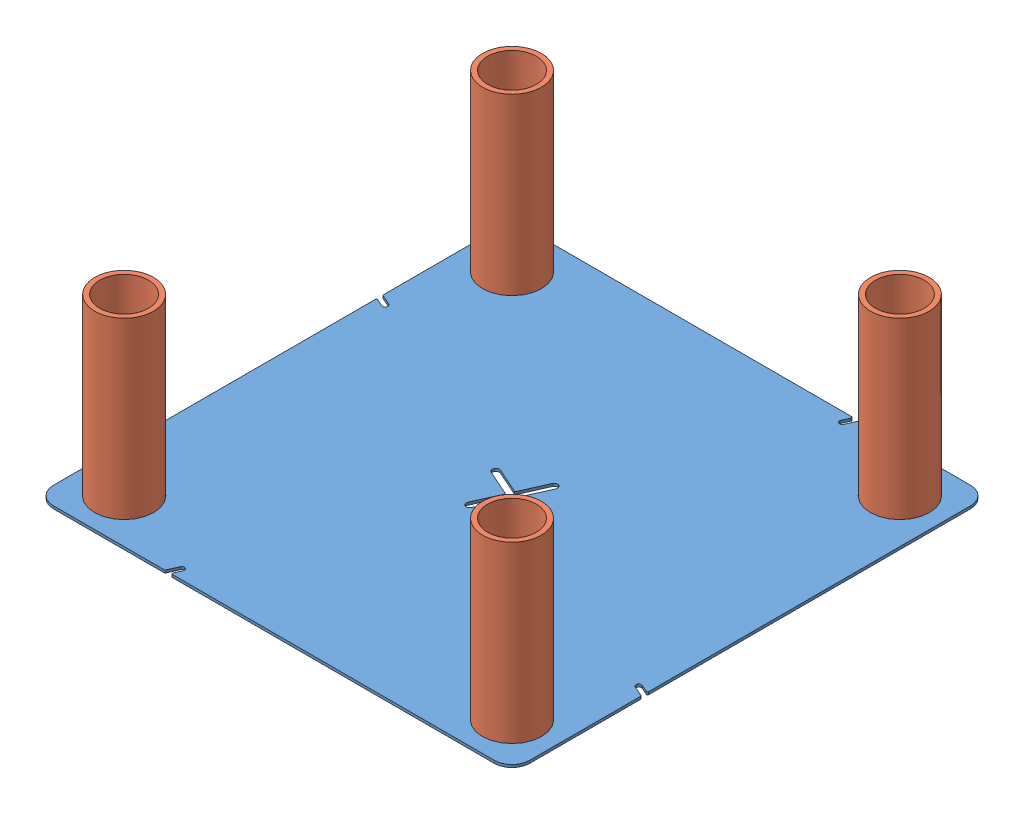
SolidWorks assembly GE-22304, configuration Default. Lengths in mm.
Overall size (341.88 127 341.88).
5 component instances, 2 part files, 11 mates.
Components (placement in the parent):
- GE-22304-01-1: GE-22304-01 [Default] at origin size (341.88 1.9 341.88)
- GE-22304-02-1: GE-22304-02 [Default] at (-139.192 0 -139.192) size (42.16 127 42.16)
- GE-22304-02-2: GE-22304-02 [Default] at (139.192 0 -139.192) size (42.16 127 42.16)
- GE-22304-02-3: GE-22304-02 [Default] at (139.192 0 139.192) size (42.16 127 42.16)
- GE-22304-02-4: GE-22304-02 [Default] at (-139.192 0 139.192) size (42.16 127 42.16)
Mates (geometry in assembly coordinates):
- Coincident1: coincident aligned: plane of GE-22304-01-1 through (0 0 0) normal (0 0 1)
- Coincident2: coincident aligned: plane of GE-22304-01-1 through (0 0 0) normal (0 1 0)
- Coincident3: coincident aligned: plane of GE-22304-01-1 through (0 0 0) normal (1 0 0)
- Coincident4: coincident aligned: plane of GE-22304-01-1 through (0 0 0) normal (0 -1 0); plane of GE-22304-02-4 through (-139.192 0 139.192) normal (0 -1 0)
- Coincident5: coincident aligned: plane of GE-22304-01-1 through (0 0 0) normal (0 -1 0); plane of GE-22304-02-1 through (-139.192 0 -139.192) normal (0 -1 0)
- Coincident6: coincident aligned: plane of GE-22304-01-1 through (0 0 0) normal (0 -1 0); plane of GE-22304-02-2 through (139.192 0 -139.192) normal (0 -1 0)
- Coincident7: coincident aligned: plane of GE-22304-01-1 through (0 0 0) normal (0 -1 0); plane of GE-22304-02-3 through (139.192 0 139.192) normal (0 -1 0)
- Concentric5: concentric anti-aligned: cylinder of GE-22304-01-1 through (-139.192 0 -139.192) axis (0 1 0) radius 21.209; cylinder of GE-22304-02-1 through (-139.192 127 -139.192) axis (0 -1 0) radius 21.082
- Concentric6: concentric anti-aligned: cylinder of GE-22304-01-1 through (139.192 0 -139.192) axis (0 1 0) radius 21.209; cylinder of GE-22304-02-2 through (139.192 127 -139.192) axis (0 -1 0) radius 21.082
- Concentric7: concentric anti-aligned: cylinder of GE-22304-01-1 through (139.192 0 139.192) axis (0 1 0) radius 21.209; cylinder of GE-22304-02-3 through (139.192 127 139.192) axis (0 -1 0) radius 21.082
- Concentric8: concentric anti-aligned: cylinder of GE-22304-01-1 through (-139.192 0 139.192) axis (0 1 0) radius 21.209; cylinder of GE-22304-02-4 through (-139.192 127 139.192) axis (0 -1 0) radius 21.082
